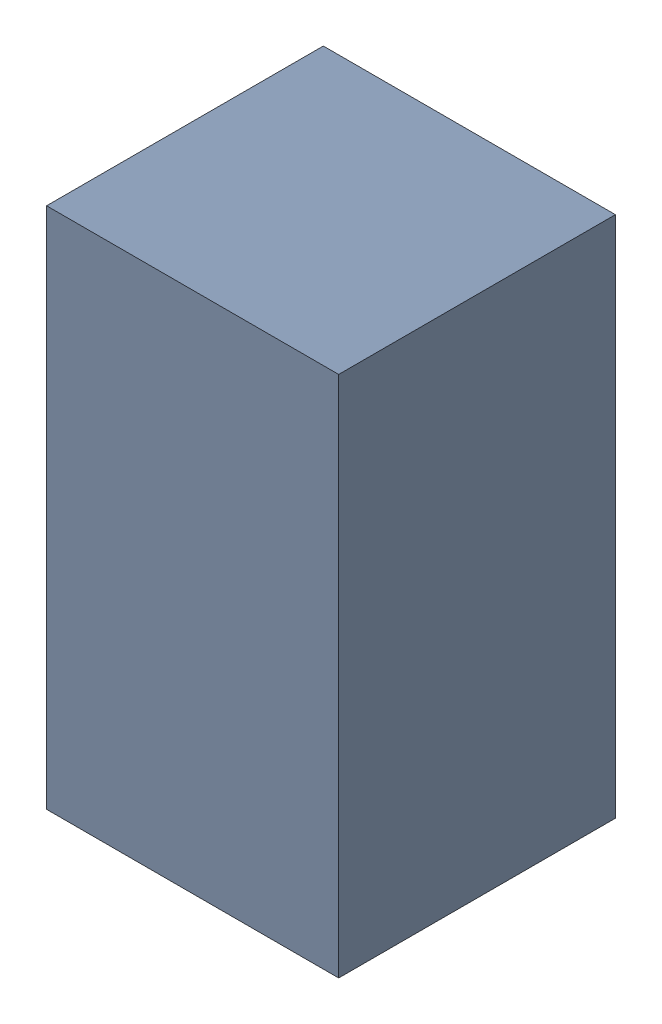
SolidWorks assembly R3_1, configuration Default. Lengths in mm.
Overall size (0.95 1.7 0.9).
2 component instances, 1 part files, 0 mates.
Components (placement in the parent):
- 5808185088-1: 5808185088 [Default] at (18.288 9.767 0) size (0.95 1.7 0.9)
  - Extruded_1_2-1: Extruded_1_2 [Default] at origin size (0.95 1.7 0.9)
